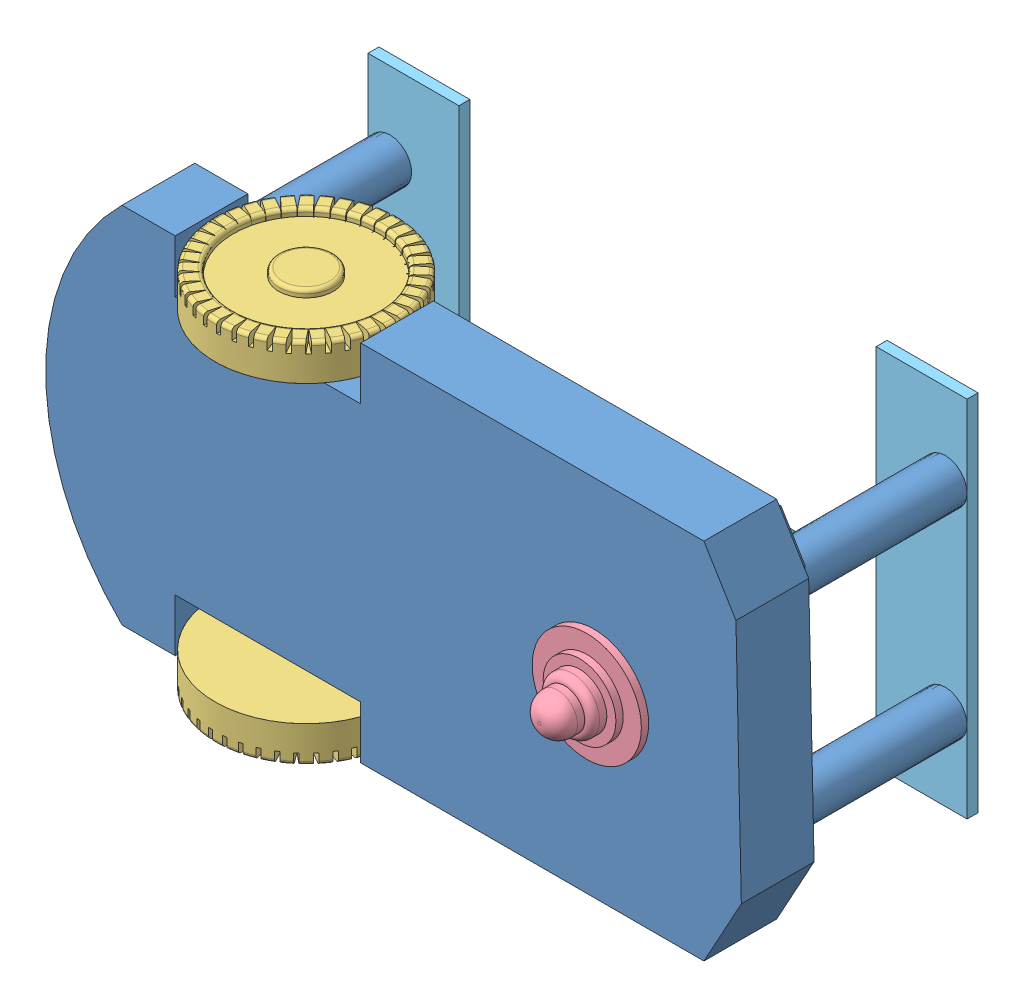
SolidWorks assembly Assem1, configuration Default. Lengths in mm.
Overall size (191.29 101.23 98.36).
9 component instances, 7 part files, 19 mates.
Components (placement in the parent):
- BASE-1: BASE [Default] at (996.2593 -171.2411 -157.0378) size (191.29 100 70)
- CHASIS ROD-1: CHASIS ROD [Default] at (-195.7938 -184.3123 -146.8178) x (0.971099 0 0.238678) z (0 1 0) size (10 10 100)
- WHEEL-1: WHEEL [Default] at (-196.8359 -93.8123 -109.1786) x (0.7492 0 0.662344) z (-0.662344 0 0.7492) size (50.11 10.12 50.11)
- WHEEL-2: WHEEL [Default] at (-195.6227 -174.8123 -109.2622) x (-0.651237 0 0.758875) z (0.758875 0 0.651237) size (50.11 10.12 50.11)
- CASTOR WHEEL-1: CASTOR WHEEL [Default] at (-102.1213 -148.5092 -137.0378) size (30 30 15)
- PLATE UPPER-1: PLATE UPPER [Default] at (-189.0116 -147.6711 -207.0378) x (0 -1 0) z (0 0 -1) size (100 25 3)
- PLATE UPPER-2: PLATE UPPER [Default] at (-49.2866 -147.6711 -207.0378) x (0 -1 0) z (0 0 -1) size (100 25 3)
- BREADBOARD-1: BREADBOARD [Default] at (-101.3768 -131.4943 -161.0378) x (0 -1 0) z (0 0 -1) size (60 40 10)
- aurdino-1: aurdino [Default] at (-180.0881 -147.4976 -166.0378) size (70 50 9)
Mates (geometry in assembly coordinates):
- Concentric1: concentric anti-aligned: circle of BASE-1; cylinder of CHASIS ROD-1 through (-198.8361 -84.3123 -147.0378) axis (0 -1 0) radius 5
- Coincident3: coincident aligned: plane of BASE-1 through (996.2593 -184.3123 -137.0378) normal (0 -1 0); plane of CHASIS ROD-1 through (-198.8361 -184.3123 -147.0378) normal (0 -1 0)
- Concentric2: concentric aligned: cylinder of CHASIS ROD-1 through (-198.8361 -84.3123 -147.0378) axis (0 -1 0) radius 5; circle of WHEEL-1
- Distance3: distance = 5 mm anti-aligned: plane of BASE-1 through (-224.8361 -98.8123 -157.0378) normal (0 1 0); plane of WHEEL-1 through (-198.8361 -93.8123 -147.0378) normal (0 -1 0)
- Concentric5: concentric anti-aligned: cylinder of CHASIS ROD-1 through (-198.8361 -84.3123 -147.0378) axis (0 -1 0) radius 5; cylinder of WHEEL-2 through (-198.8361 -174.9123 -147.0378) axis (0 1 0) radius 5
- Distance4: distance = 5 mm anti-aligned: plane of BASE-1 through (-224.8361 -169.8123 -157.0378) normal (0 -1 0); plane of WHEEL-2 through (-198.8361 -174.8123 -147.0378) normal (0 1 0)
- Coincident10: coincident anti-aligned: plane of BASE-1 through (996.2593 -171.2411 -137.0378) normal (0 0 1); plane of CASTOR WHEEL-1 through (-109.654 -135.3817 -137.0378) normal (0 0 -1)
- Lock1: lock: unknown of BASE-1; unknown of CASTOR WHEEL-1
- Coincident12: coincident anti-aligned: plane of BASE-1 through (-83.0856 -161.8956 -207.0378) normal (0 0 -1); plane of PLATE UPPER-1 through (-189.0116 -147.6711 -207.0378) normal (0 0 1)
- Parallel1: parallel aligned: plane of BASE-1 through (996.2593 -84.3123 -137.0378) normal (0 1 0); plane of PLATE UPPER-1 through (-241.8105 -84.3123 -210.0378) normal (0 1 0)
- Distance5: distance = 0 mm aligned: plane of PLATE UPPER-1 through (-241.8105 -184.3123 -210.0378) normal (0 -1 0); plane of BASE-1 through (996.2593 -184.3123 -137.0378) normal (0 -1 0)
- Coincident16: coincident anti-aligned: plane of BASE-1 through (-83.0856 -106.7291 -207.0378) normal (0 0 -1); plane of PLATE UPPER-2 through (-49.2866 -147.6711 -207.0378) normal (0 0 1)
- Coincident17: coincident aligned: plane of BASE-1 through (996.2593 -84.3123 -137.0378) normal (0 1 0); plane of PLATE UPPER-2 through (-102.0856 -84.3123 -210.0378) normal (0 1 0)
- Tangent5: tangent aligned: cylinder of BASE-1 through (-83.0856 -106.7291 -207.0378) axis (0 0 1) radius 6; plane of PLATE UPPER-2 through (-77.0856 -84.3123 -210.0378) normal (1 0 0)
- Tangent6: tangent aligned: cylinder of BASE-1 through (-235.8105 -106.7291 -207.0378) axis (0 0 1) radius 6; plane of PLATE UPPER-1 through (-241.8105 -84.3123 -210.0378) normal (-1 0 0)
- Coincident21: coincident anti-aligned: plane of BASE-1 through (-190.4583 -134.3123 -161.0378) normal (0 0 -1); plane of BREADBOARD-1 through (-101.3768 -131.4943 -161.0378) normal (0 0 1)
- Lock2: lock: unknown of BASE-1; unknown of BREADBOARD-1
- Coincident23: coincident anti-aligned: plane of BASE-1 through (-190.4583 -134.3123 -161.0378) normal (0 0 -1); plane of aurdino-1 through (-180.0881 -147.4976 -161.0378) normal (0 0 1)
- Lock3: lock: unknown of BASE-1; unknown of aurdino-1
